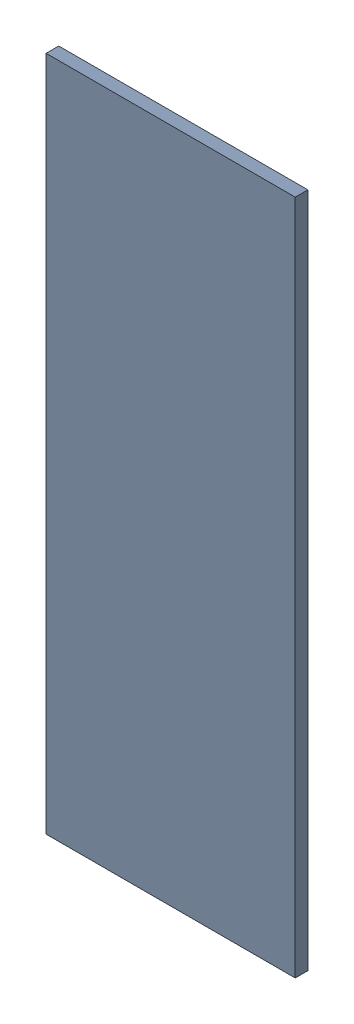
SolidWorks assembly Pad RAK4600-16(19.975mm,8.691mm) on Top Layer, configuration Predeterminado. Lengths in mm.
Overall size (0.7 1.9 0.04).
2 component instances, 1 part files, 0 mates.
Components (placement in the parent):
- Pad RAK4600-16(19.975mm,8.691mm) on Top Layer-1-1: Pad RAK4600-16(19.975mm,8.691mm) on Top Layer-1 [Predeterminado] at (-68.317 -44.187 -0.0457) size (0.7 1.9 0.04)
  - Pad RAK4600-16(19.975mm,8.691mm) on Top Layer-Part-1-1: Pad RAK4600-16(19.975mm,8.691mm) on Top Layer-Part-1 [Predeterminado] at origin size (0.7 1.9 0.04)
